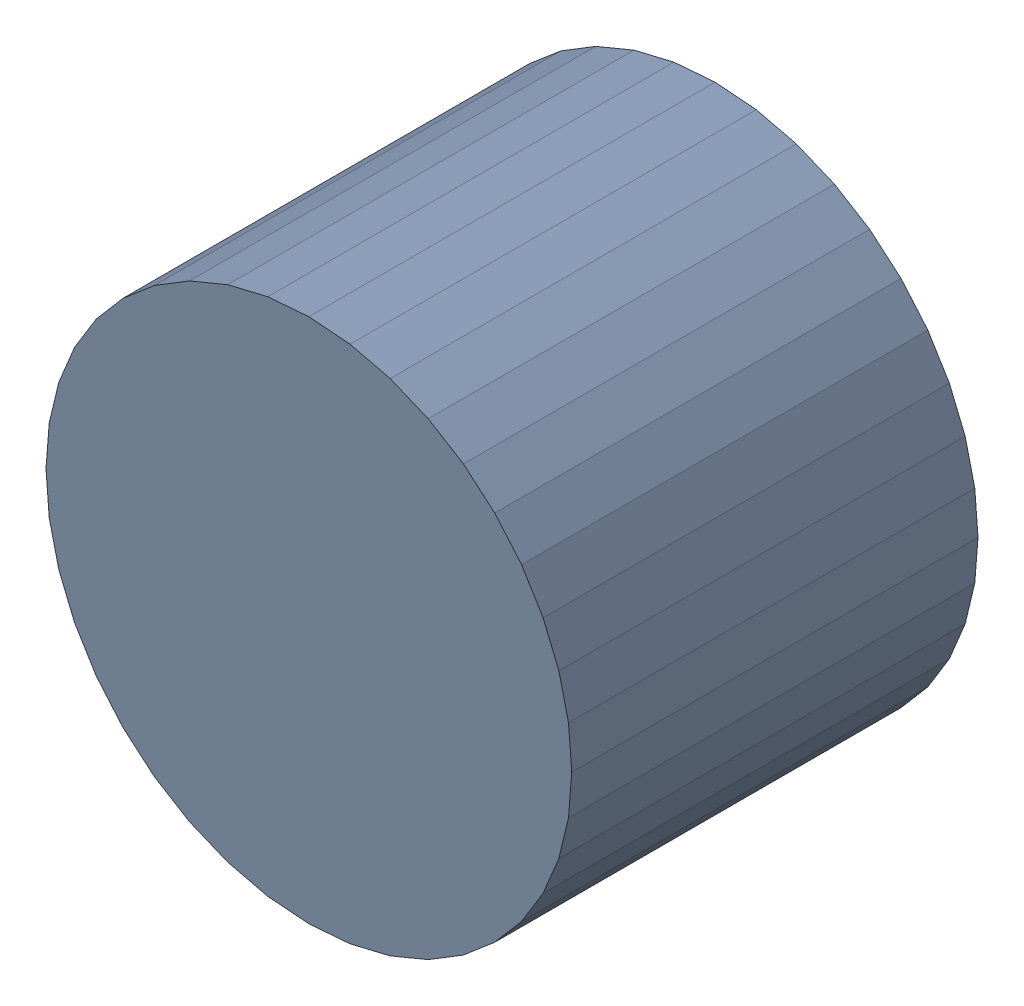
SolidWorks assembly C21Kanaloa_v2.0.0_Power, configuration Default. Lengths in mm.
Overall size (8.02 8.02 6.2).
2 component instances, 1 part files, 0 mates.
Components (placement in the parent):
- 425994496-1: 425994496 [Default] at (113.64 160.68 0) size (8.02 8.02 6.2)
  - Extruded_22-1: Extruded_22 [Default] at origin size (8.02 8.02 6.2)
